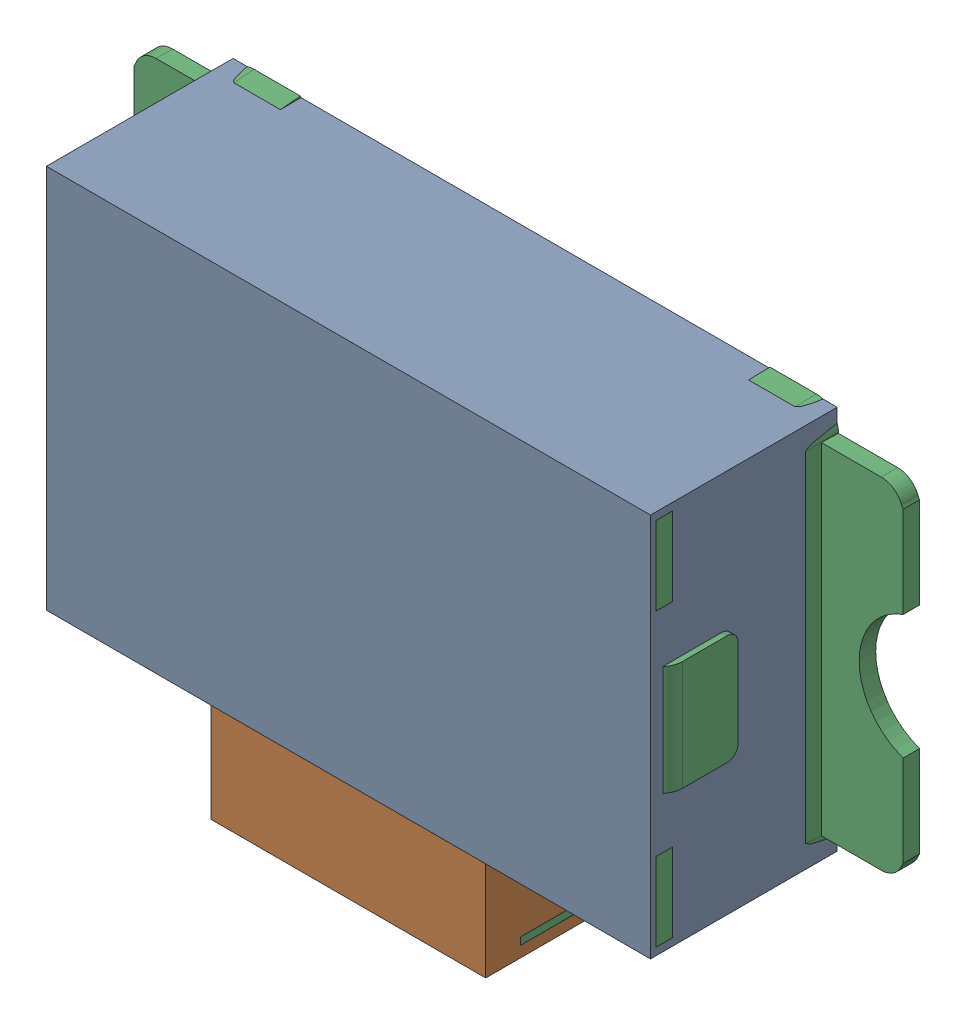
SolidWorks assembly B1, configuration Default. Lengths in mm.
Overall size (7 4.41 1.71).
5 component instances, 3 part files, 0 mates.
Components (placement in the parent):
- 1737245880-1: 1737245880 [Default] at (9.347 2.032 0) size (5.5 3.5 1.7)
  - Extruded-8-1: Extruded-8 [Default] at origin size (5.5 3.5 1.7)
- 1737246016-1: 1737246016 [Default] at (9.347 -0.168 0.6) size (2.5 0.9 1.1)
  - Extruded-9-1: Extruded-9 [Default] at origin size (2.5 0.9 1.1)
- KSS221GLFS-1: KSS221GLFS [Default] at (9.3471 2.0319 0) x (0 -1 0) z (-1 0 0) size (4.41 1.66 7)
